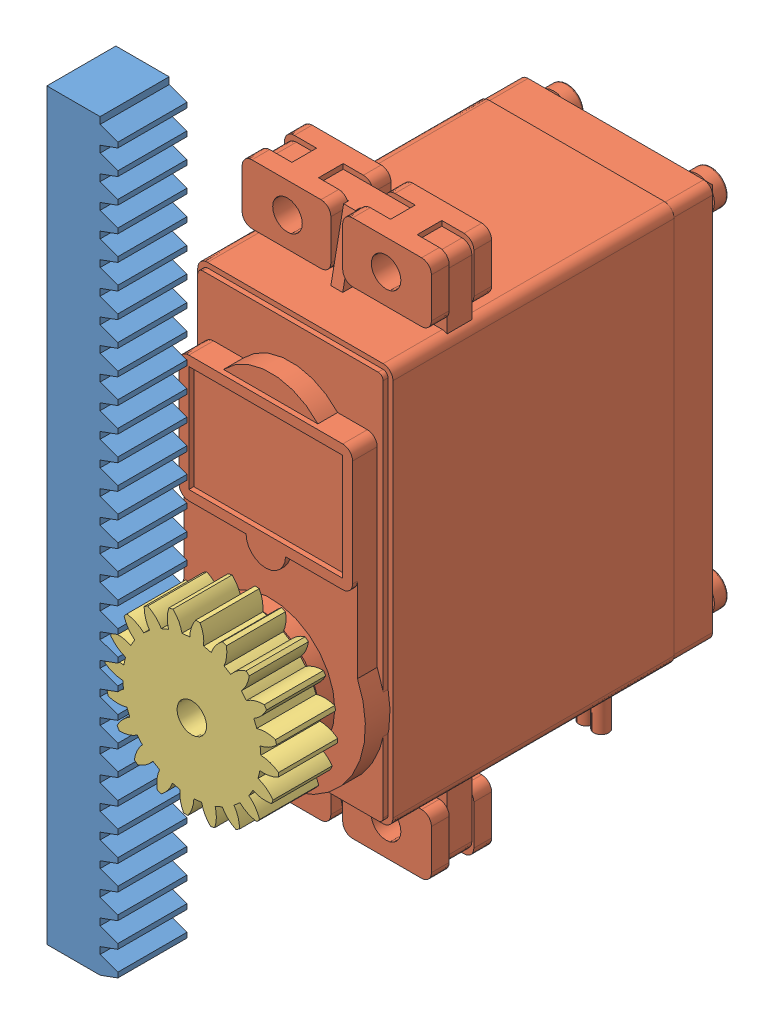
SolidWorks assembly Meccanismoret, configuration Default. Lengths in mm.
Overall size (24.67 75.4 46).
3 component instances, 3 part files, 7 mates.
Components (placement in the parent):
- Metric - Rack-spur - 2-1: Metric - Rack-spur - 2 [Metric - Rack-spur - rectangular 5M 20PA 20FW 40PH 500L---SAll] at (4.0708 283.8683 7.3051) x (0 -1 0) z (0 0 1) size (75.4 7.2 7)
- servo-1: servo [Default] at (34.8754 33.0085 -16.7949) x (0 -1 0) z (-1 0 0) size (57.55 42.8 19.8)
- Metric - Spur gear 2-1: Metric - Spur gear 2 [Metric - Spur gear 5M 20T 20PA 20FW ---S20N75H50L15N] at (34.8754 22.9085 -12.1949) x (0 0 1) z (0.225937 0.974142 0) size (6 17.45 17.45)
Mates (geometry in assembly coordinates):
- Concentrico1: concentric: cylinder of servo-1 through (34.8754 22.9085 -0.4949) axis (0 0 -1) radius 2.85; cylinder of Metric - Spur gear 2-1 through (34.8754 22.9085 -0.4949) axis (0 0 -1) radius 2.85
- Coincidente1: coincident: plane of servo-1 through (34.8754 22.9085 -0.4949) normal (0 0 1); plane of Metric - Spur gear 2-1 through (34.8754 22.9085 -0.4949) normal (0 0 -1)
- Parallelo1: parallel: plane of servo-1 through (24.9754 52.2085 -14.2949) normal (-1 0 0); plane of Metric - Rack-spur - 2-1 through (20.6754 73.7216 -4.2949) normal (-1 0 0)
- Distanza2: distance = 6.5 mm: plane of Metric - Rack-spur - 2-1 through (27.8754 73.7216 -4.2949) normal (0 0 -1); plane of Metric - Spur gear 2-1 through (37.3626 25.7267 2.2051) normal (0 0 1)
- RackPinionMate1: rack pinion = 16 mm: line of Metric - Rack-spur - 2-1 through (20.6754 71.5528 2.7051) axis (0 -1 0); cylinder of Metric - Spur gear 2-1 through (34.8754 22.9085 2.8051) axis (0 0 -1) radius 1.5
- Tangente1: tangent: plane of Metric - Rack-spur - 2-1 through (26.0754 15.5718 -4.2949) normal (1 0 0); cylinder of Metric - Spur gear 2-1 through (34.8754 22.9085 -5.3949) axis (0 0 -1) radius 8.8
- Tangente2: tangent: plane of Metric - Rack-spur - 2-1; cylinder of Metric - Spur gear 2-1 through (39.4147 16.9161 -0.5949) axis (0 0 -1) radius 3.2
